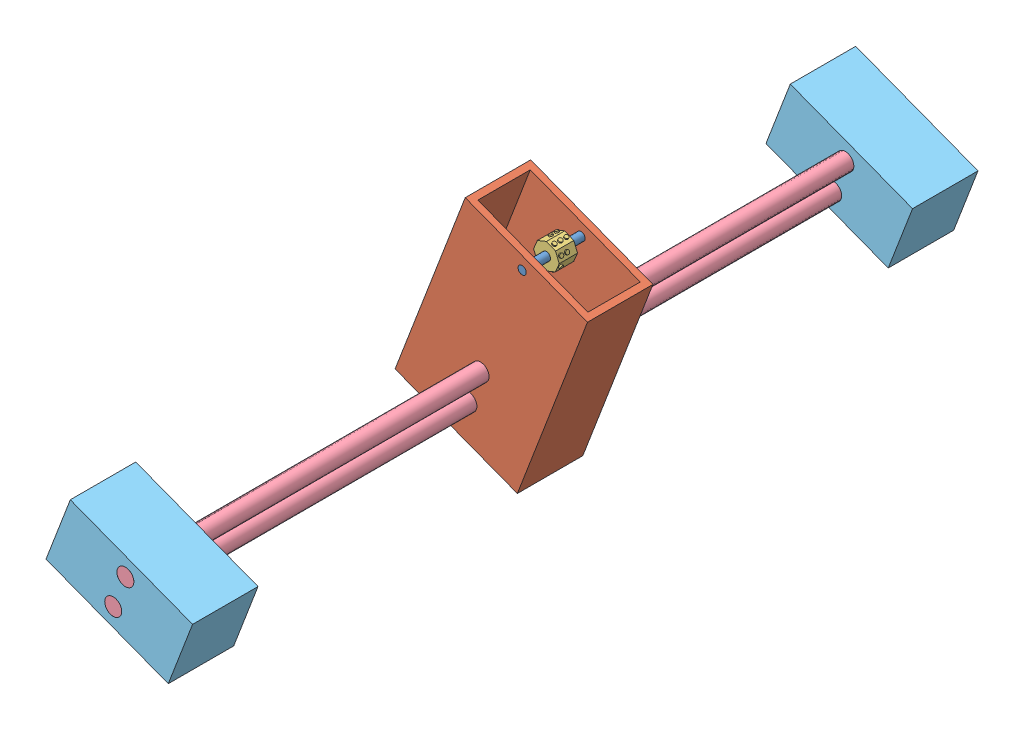
SolidWorks assembly Presser Assambly, configuration Default. Lengths in mm.
Overall size (74.67 89.32 304.8).
7 component instances, 5 part files, 14 mates.
Components (placement in the parent):
- Roller Axle 2.0-1: Roller Axle 2.0 [Default] at (13.3551 18.2656 14.0484) size (3.17 3.17 25.4)
- Roller Holder 2.0-1: Roller Holder 2.0 [Default] at (-35.9532 -39.5653 14.0484) x (0.934037 -0.357176 0) z (0 0 1) size (50.8 76.2 25.4)
- Braile Roller 2.0 -1: Braile Roller 2.0  [Default] at (13.3551 18.2656 22.9378) x (0.999979 -0.006471 0) z (0 0 1) size (9.96 9.96 7.1)
- Leadscrew 2.0-1: Leadscrew 2.0 [Default] at (-7.5111 -36.3008 -127.52) size (6.6 6.6 304.8)
- Leadscrew 2.0-2: Leadscrew 2.0 [Default] at (-2.7935 -23.9641 -127.52) size (6.6 6.6 304.8)
- Pillow Block 2.0-1: Pillow Block 2.0 [Default] at (-33.5944 -33.397 151.88) x (0.934037 -0.357176 0) z (0 0 1) size (50.8 26.42 25.4)
- Pillow Block 2.0-2: Pillow Block 2.0 [Default] at (-33.5944 -33.397 -127.52) x (0.934037 -0.357176 0) z (0 0 1) size (50.8 26.42 25.4)
Mates (geometry in assembly coordinates):
- Concentric1: concentric anti-aligned: cylinder of Roller Axle 2.0-1 through (13.3551 18.2656 39.4484) axis (0 0 -1) radius 1.5875; cylinder of Braile Roller 2.0 -1 through (13.3551 18.2656 22.9378) axis (0 0 1) radius 1.5875
- Concentric2: concentric anti-aligned: cylinder of Roller Axle 2.0-1 through (13.3551 18.2656 39.4484) axis (0 0 -1) radius 1.5875; cylinder of Roller Holder 2.0-1 through (13.3551 18.2656 14.0484) axis (0 0 1) radius 1.5875
- Coincident1: coincident aligned: plane of Roller Axle 2.0-1 through (13.3551 18.2656 39.4484) normal (0 0 1); plane of Roller Holder 2.0-1 through (-35.9532 -39.5653 39.4484) normal (0 0 1)
- Distance1: distance = 6.35 mm: point of Braile Roller 2.0 -1; line of Roller Holder 2.0-1 through (36.3402 14.371 16.5884) axis (-0.934037 0.357176 0)
- Concentric3: concentric aligned: cylinder of Roller Holder 2.0-1 through (-2.7935 -23.9641 39.4484) axis (0 0 -1) radius 3.302; cylinder of Leadscrew 2.0-2 through (-2.7935 -23.9641 177.28) axis (0 0 -1) radius 3.302
- Concentric4: concentric aligned: cylinder of Roller Holder 2.0-1 through (-7.5111 -36.3008 39.4484) axis (0 0 -1) radius 3.302; cylinder of Leadscrew 2.0-1 through (-7.5111 -36.3008 177.28) axis (0 0 -1) radius 3.302
- Concentric5: concentric aligned: cylinder of Leadscrew 2.0-2 through (-2.7935 -23.9641 177.28) axis (0 0 -1) radius 3.302; cylinder of Pillow Block 2.0-1 through (-2.7935 -23.9641 177.28) axis (0 0 -1) radius 3.302
- Concentric6: concentric aligned: cylinder of Leadscrew 2.0-1 through (-7.5111 -36.3008 177.28) axis (0 0 -1) radius 3.302; cylinder of Pillow Block 2.0-1 through (-7.5111 -36.3008 177.28) axis (0 0 -1) radius 3.302
- Coincident3: coincident aligned: plane of Leadscrew 2.0-1 through (-7.5111 -36.3008 177.28) normal (0 0 1); plane of Pillow Block 2.0-1 through (-33.5944 -33.397 177.28) normal (0 0 1)
- Coincident4: coincident aligned: plane of Leadscrew 2.0-2 through (-2.7935 -23.9641 177.28) normal (0 0 1); plane of Pillow Block 2.0-1 through (-33.5944 -33.397 177.28) normal (0 0 1)
- Concentric7: concentric aligned: cylinder of Leadscrew 2.0-1 through (-7.5111 -36.3008 177.28) axis (0 0 -1) radius 3.302; cylinder of Pillow Block 2.0-2 through (-7.5111 -36.3008 -102.12) axis (0 0 -1) radius 3.302
- Concentric8: concentric aligned: cylinder of Leadscrew 2.0-2 through (-2.7935 -23.9641 177.28) axis (0 0 -1) radius 3.302; cylinder of Pillow Block 2.0-2 through (-2.7935 -23.9641 -102.12) axis (0 0 -1) radius 3.302
- Coincident5: coincident aligned: plane of Leadscrew 2.0-2 through (-2.7935 -23.9641 -127.52) normal (0 0 -1); plane of Pillow Block 2.0-2 through (-33.5944 -33.397 -127.52) normal (0 0 -1)
- Coincident6: coincident aligned: plane of Leadscrew 2.0-1 through (-7.5111 -36.3008 -127.52) normal (0 0 -1); plane of Pillow Block 2.0-2 through (-33.5944 -33.397 -127.52) normal (0 0 -1)
